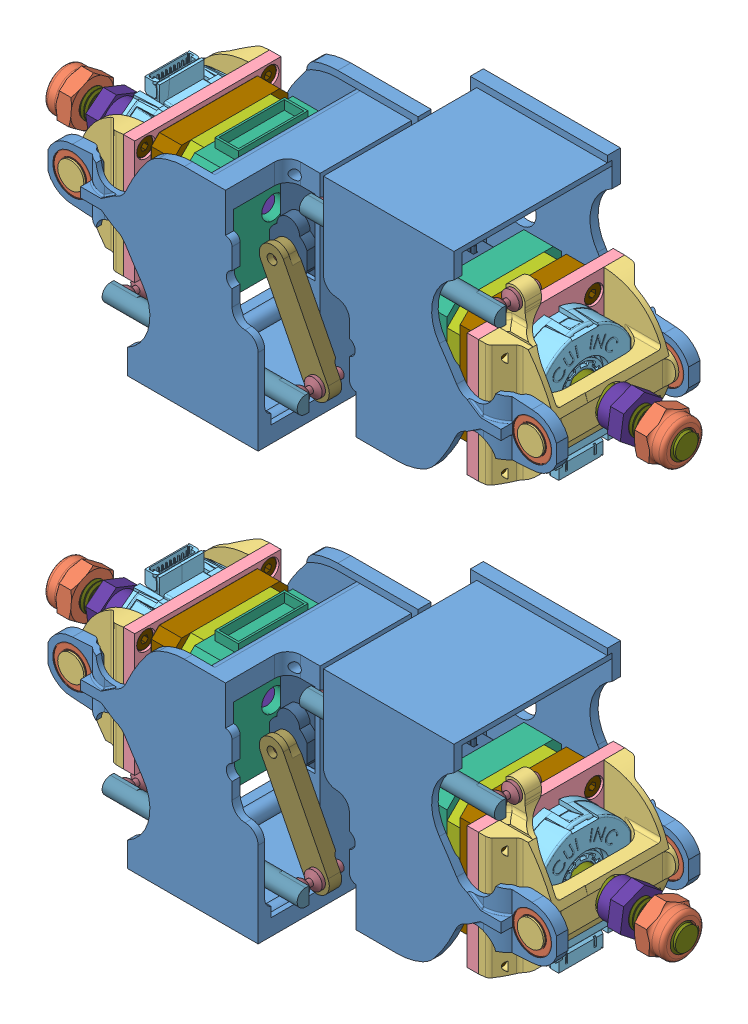
SolidWorks assembly Chassis assembly, configuration Default. Lengths in mm.
Overall size (191.69 235 56).
145 component instances, 22 part files, 13 mates.
Components (placement in the parent):
- Chassis test-1: Chassis test [Default] at (243.7771 53.5419 144.9744) size (100.25 235 0)
- Module Assembly-1: Module Assembly [Default] at (19.8721 170.9374 177.4744) x (0 1 0) z (-1 0 0) size (68.25 51.28 97.81)
  - Housing-1: Housing [Default] at origin size (64.25 48.5 67.91)
  - Bearing 12x8-1: Bearing 12x8 [Default] at (0 -18.25 0.75) x (-0.914388 0 0.40484) z (-0.40484 0 -0.914388) size (12 3.5 12)
  - Spindle-1: Spindle [Default] at (0 2 0.75) size (49.04 45 20.5)
  - Spindle base-1: Spindle base [Default] at (0 2 -15.25) x (-1 0 0) z (0 -1 0) size (37.62 3.5 44.8)
  - Encoder-1: Encoder [Défaut] at (0 2 -12.48) x (0 1 0) z (0 0 1) size (28.68 37.25 10.4)
  - Wheel-1: Wheel [Default] at (0 2 -8.55) x (0.929787 0.368098 0) z (0.368098 -0.929787 0) size (81.5 31 81.5) (hidden)
  - Stepper Nema14-1: Stepper Nema14 [Predeterminado] at (4.764 -15.5 -30.1157) x (-1 0 0) z (0 1 0) size (37.8 40 35)
    - nema14_base-1: nema14_base [Predeterminado] at (-12.736 -8.6343 35) size (37.8 9 35)
    - nema14_centro-1: nema14_centro [Predeterminado] at (-12.736 0.3657 35) size (35 4 35)
    - nema14_eje-1: nema14_eje [Predeterminado] at (4.764 -6.6343 17.5) x (0 1 0) z (-0.939004 0 0.343907) size (38 5 5)
    - nema14_techo-1: nema14_techo [Predeterminado] at (-12.736 4.3657 35) size (35 9 35)
  - Servo motor-1: Servo motor [Default] at (-25.7048 26.288 -66.0832) x (0 0 1) z (1 0 0) size (11.5 29.2 32.5) (flexible)
    - TowerPro-SG90-Body-1: TowerPro-SG90-Body [Default] at (13.6721 7.288 30.7048) size (11.5 26 32.5)
    - ServoFinalGear-1: ServoFinalGear [Default] at (13.6721 33.288 25.7048) x (0.607544 0 -0.794286) z (0.794286 0 0.607544) size (4.64 3.2 4.64)
  - Control arm-1: Control arm [Default] at (0 -7.5 -52.4111) x (0.891007 0 0.45399) z (0.45399 0 -0.891007) size (37.9 4.5 7.8)
  - Ball joint assy-1: Ball joint assy [Default] at (-26.7302 -5 -12.8697) x (-0.874356 0 0.485286) z (0.485286 0 0.874356) size (15.43 16.21 22.24) (flexible)
    - Ball-1: Ball [Default] at origin size (5.5 15.11 5.5)
    - Joint-1: Joint [Default] at (-3.8823 13.66 -6.9948) x (0.874356 0 -0.485286) z (0 -1 0) size (5.1 22.6 5.1)
  - Ball joint assy-2: Ball joint assy [Default] at (-26.7302 -5 -66.0308) x (-0.846813 0 0.531891) z (0.531891 0 0.846813) size (16.34 16.21 21.85) (flexible)
    - Ball-1: Ball [Default] at origin size (5.5 15.11 5.5)
    - Joint-1: Joint [Default] at (4.2551 13.66 6.7745) x (-0.846813 0 0.531891) z (0 -1 0) size (5.1 22.6 5.1)
  - Steering rod-1: Steering rod [Default] at (-26.7302 -18.66 -18.4608) x (-0.014502 0.999895 0) z (-0.999895 -0.014502 0) size (3 28.27 3)
  - Wheel adapter-1: Wheel adapter [Default] at (0 2 -13.8175) x (0.291296 -0.956633 0) z (-0.956633 -0.291296 0) size (8.34 40 8.37)
  - Wheel spacer-1: Wheel spacer [Default] at (0 2 12.25) x (0.368098 -0.929787 0) z (0.929787 0.368098 0) size (13.86 8 12)
  - M3x5 din 7984-1: M3x5 din 7984 [Default] at (15.31 20.9 -16.25) x (0.933505 0.358563 0) z (0 0 -1) size (5.5 5.5 7)
  - Housing lid-1: Housing lid [Default] at (0 4 0) x (-1 0 0) z (0 0 1) size (68.25 9.28 69.91)
  - Bearing 12x8-3: Bearing 12x8 [Default] at (0 22.25 0.75) x (-0.914388 0 0.40484) z (0.40484 0 0.914388) size (12 3.5 12)
  - M8 nut-1: M8 nut [Default] at (0 2 16.6825) x (-0.817347 -0.576146 0) z (0 0 1) size (13 16.06 8.5)
  - M3x5 din 7984-2: M3x5 din 7984 [Default] at (15.31 -16.9 -16.25) x (-0.933505 0.358563 0) z (0 0 -1) size (5.5 5.5 7)
  - M3x5 din 7984-3: M3x5 din 7984 [Default] at (-15.31 20.9 -16.25) x (0.933505 -0.358563 0) z (0 0 -1) size (5.5 5.5 7)
  - M3x5 din 7984-4: M3x5 din 7984 [Default] at (-15.31 -16.9 -16.25) x (-0.933505 -0.358563 0) z (0 0 -1) size (5.5 5.5 7)
  - M3x5 din 7984-5: M3x5 din 7984 [Default] at (-13 15 -17.75) x (0.999849 0.017374 0) z (0 0 1) size (5.5 5.5 7)
  - M3x5 din 7984-6: M3x5 din 7984 [Default] at (-13 -11 -17.75) x (-0.999849 0.017374 0) z (0 0 1) size (5.5 5.5 7)
  - M3x5 din 7984-7: M3x5 din 7984 [Default] at (13 15 -17.75) x (0.999849 -0.017374 0) z (0 0 1) size (5.5 5.5 7)
  - M3x5 din 7984-8: M3x5 din 7984 [Default] at (13 -11 -17.75) x (-0.999849 -0.017374 0) z (0 0 1) size (5.5 5.5 7)
- Module Assembly-2: Module Assembly [Default] at (19.8721 40.1874 177.4744) x (0 1 0) z (-1 0 0) size (68.25 51.28 97.81)
  - Housing-1: Housing [Default] at origin size (64.25 48.5 67.91)
  - Bearing 12x8-1: Bearing 12x8 [Default] at (0 -18.25 0.75) x (-0.914388 0 0.40484) z (-0.40484 0 -0.914388) size (12 3.5 12)
  - Spindle-1: Spindle [Default] at (0 2 0.75) size (49.04 45 20.5)
  - Spindle base-1: Spindle base [Default] at (0 2 -15.25) x (-1 0 0) z (0 -1 0) size (37.62 3.5 44.8)
  - Encoder-1: Encoder [Défaut] at (0 2 -12.48) x (0 1 0) z (0 0 1) size (28.68 37.25 10.4)
  - Wheel-1: Wheel [Default] at (0 2 -8.55) x (0.929787 0.368098 0) z (0.368098 -0.929787 0) size (81.5 31 81.5) (hidden)
  - Stepper Nema14-1: Stepper Nema14 [Predeterminado] at (4.764 -15.5 -30.1157) x (-1 0 0) z (0 1 0) size (37.8 40 35)
    - nema14_base-1: nema14_base [Predeterminado] at (-12.736 -8.6343 35) size (37.8 9 35)
    - nema14_centro-1: nema14_centro [Predeterminado] at (-12.736 0.3657 35) size (35 4 35)
    - nema14_eje-1: nema14_eje [Predeterminado] at (4.764 -6.6343 17.5) x (0 1 0) z (-0.939004 0 0.343907) size (38 5 5)
    - nema14_techo-1: nema14_techo [Predeterminado] at (-12.736 4.3657 35) size (35 9 35)
  - Servo motor-1: Servo motor [Default] at (-25.7048 26.288 -66.0832) x (0 0 1) z (1 0 0) size (11.5 29.2 32.5) (flexible)
    - TowerPro-SG90-Body-1: TowerPro-SG90-Body [Default] at (13.6721 7.288 30.7048) size (11.5 26 32.5)
    - ServoFinalGear-1: ServoFinalGear [Default] at (13.6721 33.288 25.7048) x (0.607544 0 -0.794286) z (0.794286 0 0.607544) size (4.64 3.2 4.64)
  - Control arm-1: Control arm [Default] at (0 -7.5 -52.4111) x (0.891007 0 0.45399) z (0.45399 0 -0.891007) size (37.9 4.5 7.8)
  - Ball joint assy-1: Ball joint assy [Default] at (-26.7302 -5 -12.8697) x (-0.874356 0 0.485286) z (0.485286 0 0.874356) size (15.43 16.21 22.24) (flexible)
    - Ball-1: Ball [Default] at origin size (5.5 15.11 5.5)
    - Joint-1: Joint [Default] at (-3.8823 13.66 -6.9948) x (0.874356 0 -0.485286) z (0 -1 0) size (5.1 22.6 5.1)
  - Ball joint assy-2: Ball joint assy [Default] at (-26.7302 -5 -66.0308) x (-0.846813 0 0.531891) z (0.531891 0 0.846813) size (16.34 16.21 21.85) (flexible)
    - Ball-1: Ball [Default] at origin size (5.5 15.11 5.5)
    - Joint-1: Joint [Default] at (4.2551 13.66 6.7745) x (-0.846813 0 0.531891) z (0 -1 0) size (5.1 22.6 5.1)
  - Steering rod-1: Steering rod [Default] at (-26.7302 -18.66 -18.4608) x (-0.014502 0.999895 0) z (-0.999895 -0.014502 0) size (3 28.27 3)
  - Wheel adapter-1: Wheel adapter [Default] at (0 2 -13.8175) x (0.291296 -0.956633 0) z (-0.956633 -0.291296 0) size (8.34 40 8.37)
  - Wheel spacer-1: Wheel spacer [Default] at (0 2 12.25) x (0.368098 -0.929787 0) z (0.929787 0.368098 0) size (13.86 8 12)
  - M3x5 din 7984-1: M3x5 din 7984 [Default] at (15.31 20.9 -16.25) x (0.933505 0.358563 0) z (0 0 -1) size (5.5 5.5 7)
  - Housing lid-1: Housing lid [Default] at (0 4 0) x (-1 0 0) z (0 0 1) size (68.25 9.28 69.91)
  - Bearing 12x8-3: Bearing 12x8 [Default] at (0 22.25 0.75) x (-0.914388 0 0.40484) z (0.40484 0 0.914388) size (12 3.5 12)
  - M8 nut-1: M8 nut [Default] at (0 2 16.6825) x (-0.817347 -0.576146 0) z (0 0 1) size (13 16.06 8.5)
  - M3x5 din 7984-2: M3x5 din 7984 [Default] at (15.31 -16.9 -16.25) x (-0.933505 0.358563 0) z (0 0 -1) size (5.5 5.5 7)
  - M3x5 din 7984-3: M3x5 din 7984 [Default] at (-15.31 20.9 -16.25) x (0.933505 -0.358563 0) z (0 0 -1) size (5.5 5.5 7)
  - M3x5 din 7984-4: M3x5 din 7984 [Default] at (-15.31 -16.9 -16.25) x (-0.933505 -0.358563 0) z (0 0 -1) size (5.5 5.5 7)
  - M3x5 din 7984-5: M3x5 din 7984 [Default] at (-13 15 -17.75) x (0.999849 0.017374 0) z (0 0 1) size (5.5 5.5 7)
  - M3x5 din 7984-6: M3x5 din 7984 [Default] at (-13 -11 -17.75) x (-0.999849 0.017374 0) z (0 0 1) size (5.5 5.5 7)
  - M3x5 din 7984-7: M3x5 din 7984 [Default] at (13 15 -17.75) x (0.999849 -0.017374 0) z (0 0 1) size (5.5 5.5 7)
  - M3x5 din 7984-8: M3x5 din 7984 [Default] at (13 -11 -17.75) x (-0.999849 -0.017374 0) z (0 0 1) size (5.5 5.5 7)
- Module Assembly-3: Module Assembly [Default] at (159.1944 170.9374 177.4744) x (0 -1 0) z (1 0 0) size (68.25 51.28 97.81)
  - Housing-1: Housing [Default] at origin size (64.25 48.5 67.91)
  - Bearing 12x8-1: Bearing 12x8 [Default] at (0 -18.25 0.75) x (-0.914388 0 0.40484) z (-0.40484 0 -0.914388) size (12 3.5 12)
  - Spindle-1: Spindle [Default] at (0 2 0.75) size (49.04 45 20.5)
  - Spindle base-1: Spindle base [Default] at (0 2 -15.25) x (-1 0 0) z (0 -1 0) size (37.62 3.5 44.8)
  - Encoder-1: Encoder [Défaut] at (0 2 -12.48) x (0 1 0) z (0 0 1) size (28.68 37.25 10.4)
  - Wheel-1: Wheel [Default] at (0 2 -8.55) x (0.929787 0.368098 0) z (0.368098 -0.929787 0) size (81.5 31 81.5) (hidden)
  - Stepper Nema14-1: Stepper Nema14 [Predeterminado] at (4.764 -15.5 -30.1157) x (-1 0 0) z (0 1 0) size (37.8 40 35)
    - nema14_base-1: nema14_base [Predeterminado] at (-12.736 -8.6343 35) size (37.8 9 35)
    - nema14_centro-1: nema14_centro [Predeterminado] at (-12.736 0.3657 35) size (35 4 35)
    - nema14_eje-1: nema14_eje [Predeterminado] at (4.764 -6.6343 17.5) x (0 1 0) z (-0.939004 0 0.343907) size (38 5 5)
    - nema14_techo-1: nema14_techo [Predeterminado] at (-12.736 4.3657 35) size (35 9 35)
  - Servo motor-1: Servo motor [Default] at (-25.7048 26.288 -66.0832) x (0 0 1) z (1 0 0) size (11.5 29.2 32.5) (flexible)
    - TowerPro-SG90-Body-1: TowerPro-SG90-Body [Default] at (13.6721 7.288 30.7048) size (11.5 26 32.5)
    - ServoFinalGear-1: ServoFinalGear [Default] at (13.6721 33.288 25.7048) x (0.607544 0 -0.794286) z (0.794286 0 0.607544) size (4.64 3.2 4.64)
  - Control arm-1: Control arm [Default] at (0 -7.5 -52.4111) x (0.891007 0 0.45399) z (0.45399 0 -0.891007) size (37.9 4.5 7.8)
  - Ball joint assy-1: Ball joint assy [Default] at (-26.7302 -5 -12.8697) x (-0.874356 0 0.485286) z (0.485286 0 0.874356) size (15.43 16.21 22.24) (flexible)
    - Ball-1: Ball [Default] at origin size (5.5 15.11 5.5)
    - Joint-1: Joint [Default] at (-3.8823 13.66 -6.9948) x (0.874356 0 -0.485286) z (0 -1 0) size (5.1 22.6 5.1)
  - Ball joint assy-2: Ball joint assy [Default] at (-26.7302 -5 -66.0308) x (-0.846813 0 0.531891) z (0.531891 0 0.846813) size (16.34 16.21 21.85) (flexible)
    - Ball-1: Ball [Default] at origin size (5.5 15.11 5.5)
    - Joint-1: Joint [Default] at (4.2551 13.66 6.7745) x (-0.846813 0 0.531891) z (0 -1 0) size (5.1 22.6 5.1)
  - Steering rod-1: Steering rod [Default] at (-26.7302 -18.66 -18.4608) x (-0.014502 0.999895 0) z (-0.999895 -0.014502 0) size (3 28.27 3)
  - Wheel adapter-1: Wheel adapter [Default] at (0 2 -13.8175) x (0.291296 -0.956633 0) z (-0.956633 -0.291296 0) size (8.34 40 8.37)
  - Wheel spacer-1: Wheel spacer [Default] at (0 2 12.25) x (0.368098 -0.929787 0) z (0.929787 0.368098 0) size (13.86 8 12)
  - M3x5 din 7984-1: M3x5 din 7984 [Default] at (15.31 20.9 -16.25) x (0.933505 0.358563 0) z (0 0 -1) size (5.5 5.5 7)
  - Housing lid-1: Housing lid [Default] at (0 4 0) x (-1 0 0) z (0 0 1) size (68.25 9.28 69.91)
  - Bearing 12x8-3: Bearing 12x8 [Default] at (0 22.25 0.75) x (-0.914388 0 0.40484) z (0.40484 0 0.914388) size (12 3.5 12)
  - M8 nut-1: M8 nut [Default] at (0 2 16.6825) x (-0.817347 -0.576146 0) z (0 0 1) size (13 16.06 8.5)
  - M3x5 din 7984-2: M3x5 din 7984 [Default] at (15.31 -16.9 -16.25) x (-0.933505 0.358563 0) z (0 0 -1) size (5.5 5.5 7)
  - M3x5 din 7984-3: M3x5 din 7984 [Default] at (-15.31 20.9 -16.25) x (0.933505 -0.358563 0) z (0 0 -1) size (5.5 5.5 7)
  - M3x5 din 7984-4: M3x5 din 7984 [Default] at (-15.31 -16.9 -16.25) x (-0.933505 -0.358563 0) z (0 0 -1) size (5.5 5.5 7)
  - M3x5 din 7984-5: M3x5 din 7984 [Default] at (-13 15 -17.75) x (0.999849 0.017374 0) z (0 0 1) size (5.5 5.5 7)
  - M3x5 din 7984-6: M3x5 din 7984 [Default] at (-13 -11 -17.75) x (-0.999849 0.017374 0) z (0 0 1) size (5.5 5.5 7)
  - M3x5 din 7984-7: M3x5 din 7984 [Default] at (13 15 -17.75) x (0.999849 -0.017374 0) z (0 0 1) size (5.5 5.5 7)
  - M3x5 din 7984-8: M3x5 din 7984 [Default] at (13 -11 -17.75) x (-0.999849 -0.017374 0) z (0 0 1) size (5.5 5.5 7)
- Module Assembly-4: Module Assembly [Default] at (159.1944 40.1874 177.4744) x (0 -1 0) z (1 0 0) size (68.25 51.28 97.81)
  - Housing-1: Housing [Default] at origin size (64.25 48.5 67.91)
  - Bearing 12x8-1: Bearing 12x8 [Default] at (0 -18.25 0.75) x (-0.914388 0 0.40484) z (-0.40484 0 -0.914388) size (12 3.5 12)
  - Spindle-1: Spindle [Default] at (0 2 0.75) size (49.04 45 20.5)
  - Spindle base-1: Spindle base [Default] at (0 2 -15.25) x (-1 0 0) z (0 -1 0) size (37.62 3.5 44.8)
  - Encoder-1: Encoder [Défaut] at (0 2 -12.48) x (0 1 0) z (0 0 1) size (28.68 37.25 10.4)
  - Wheel-1: Wheel [Default] at (0 2 -8.55) x (0.929787 0.368098 0) z (0.368098 -0.929787 0) size (81.5 31 81.5) (hidden)
  - Stepper Nema14-1: Stepper Nema14 [Predeterminado] at (4.764 -15.5 -30.1157) x (-1 0 0) z (0 1 0) size (37.8 40 35)
    - nema14_base-1: nema14_base [Predeterminado] at (-12.736 -8.6343 35) size (37.8 9 35)
    - nema14_centro-1: nema14_centro [Predeterminado] at (-12.736 0.3657 35) size (35 4 35)
    - nema14_eje-1: nema14_eje [Predeterminado] at (4.764 -6.6343 17.5) x (0 1 0) z (-0.939004 0 0.343907) size (38 5 5)
    - nema14_techo-1: nema14_techo [Predeterminado] at (-12.736 4.3657 35) size (35 9 35)
  - Servo motor-1: Servo motor [Default] at (-25.7048 26.288 -66.0832) x (0 0 1) z (1 0 0) size (11.5 29.2 32.5) (flexible)
    - TowerPro-SG90-Body-1: TowerPro-SG90-Body [Default] at (13.6721 7.288 30.7048) size (11.5 26 32.5)
    - ServoFinalGear-1: ServoFinalGear [Default] at (13.6721 33.288 25.7048) x (0.607544 0 -0.794286) z (0.794286 0 0.607544) size (4.64 3.2 4.64)
  - Control arm-1: Control arm [Default] at (0 -7.5 -52.4111) x (0.891007 0 0.45399) z (0.45399 0 -0.891007) size (37.9 4.5 7.8)
  - Ball joint assy-1: Ball joint assy [Default] at (-26.7302 -5 -12.8697) x (-0.874356 0 0.485286) z (0.485286 0 0.874356) size (15.43 16.21 22.24) (flexible)
    - Ball-1: Ball [Default] at origin size (5.5 15.11 5.5)
    - Joint-1: Joint [Default] at (-3.8823 13.66 -6.9948) x (0.874356 0 -0.485286) z (0 -1 0) size (5.1 22.6 5.1)
  - Ball joint assy-2: Ball joint assy [Default] at (-26.7302 -5 -66.0308) x (-0.846813 0 0.531891) z (0.531891 0 0.846813) size (16.34 16.21 21.85) (flexible)
    - Ball-1: Ball [Default] at origin size (5.5 15.11 5.5)
    - Joint-1: Joint [Default] at (4.2551 13.66 6.7745) x (-0.846813 0 0.531891) z (0 -1 0) size (5.1 22.6 5.1)
  - Steering rod-1: Steering rod [Default] at (-26.7302 -18.66 -18.4608) x (-0.014502 0.999895 0) z (-0.999895 -0.014502 0) size (3 28.27 3)
  - Wheel adapter-1: Wheel adapter [Default] at (0 2 -13.8175) x (0.291296 -0.956633 0) z (-0.956633 -0.291296 0) size (8.34 40 8.37)
  - Wheel spacer-1: Wheel spacer [Default] at (0 2 12.25) x (0.368098 -0.929787 0) z (0.929787 0.368098 0) size (13.86 8 12)
  - M3x5 din 7984-1: M3x5 din 7984 [Default] at (15.31 20.9 -16.25) x (0.933505 0.358563 0) z (0 0 -1) size (5.5 5.5 7)
  - Housing lid-1: Housing lid [Default] at (0 4 0) x (-1 0 0) z (0 0 1) size (68.25 9.28 69.91)
  - Bearing 12x8-3: Bearing 12x8 [Default] at (0 22.25 0.75) x (-0.914388 0 0.40484) z (0.40484 0 0.914388) size (12 3.5 12)
  - M8 nut-1: M8 nut [Default] at (0 2 16.6825) x (-0.817347 -0.576146 0) z (0 0 1) size (13 16.06 8.5)
  - M3x5 din 7984-2: M3x5 din 7984 [Default] at (15.31 -16.9 -16.25) x (-0.933505 0.358563 0) z (0 0 -1) size (5.5 5.5 7)
  - M3x5 din 7984-3: M3x5 din 7984 [Default] at (-15.31 20.9 -16.25) x (0.933505 -0.358563 0) z (0 0 -1) size (5.5 5.5 7)
  - M3x5 din 7984-4: M3x5 din 7984 [Default] at (-15.31 -16.9 -16.25) x (-0.933505 -0.358563 0) z (0 0 -1) size (5.5 5.5 7)
  - M3x5 din 7984-5: M3x5 din 7984 [Default] at (-13 15 -17.75) x (0.999849 0.017374 0) z (0 0 1) size (5.5 5.5 7)
  - M3x5 din 7984-6: M3x5 din 7984 [Default] at (-13 -11 -17.75) x (-0.999849 0.017374 0) z (0 0 1) size (5.5 5.5 7)
  - M3x5 din 7984-7: M3x5 din 7984 [Default] at (13 15 -17.75) x (0.999849 -0.017374 0) z (0 0 1) size (5.5 5.5 7)
  - M3x5 din 7984-8: M3x5 din 7984 [Default] at (13 -11 -17.75) x (-0.999849 -0.017374 0) z (0 0 1) size (5.5 5.5 7)
Mates (geometry in assembly coordinates):
- Coincident1: coincident: plane of Chassis test-1 through (243.7771 53.5419 149.9744) normal (0 0 1); plane of Module Assembly-1/Housing lid-1 through (19.8721 170.9374 149.9744) normal (0 0 -1)
- Parallel2: parallel: line of Chassis test-1 through (139.5332 221.6874 149.9744) axis (-1 0 0); line of Module Assembly-1/Housing lid-1 through (81.5332 195.6874 149.9744) axis (-1 0 0)
- Coincident4: coincident: plane of Chassis test-1 through (39.5332 221.6874 149.9744) normal (-1 0 0); plane of Module Assembly-1/Housing lid-1 through (39.5332 170.9374 152.4744) normal (-1 0 0)
- Coincident6: coincident: plane of Chassis test-1 through (243.7771 53.5419 149.9744) normal (0 0 1); plane of Module Assembly-2/Housing lid-1 through (19.8721 40.1874 149.9744) normal (0 0 -1)
- Coincident7: coincident: plane of Chassis test-1 through (39.5332 221.6874 149.9744) normal (-1 0 0); plane of Module Assembly-2/Housing lid-1 through (39.5332 40.1874 152.4744) normal (-1 0 0)
- Distance2: distance = 10 mm: plane of Module Assembly-2/Housing lid-1 through (19.8721 -3.3126 153.9744) normal (0 -1 0); plane of Chassis test-1 through (39.5332 -13.3126 149.9744) normal (0 -1 0)
- Coincident9: coincident: plane of Chassis test-1 through (243.7771 53.5419 149.9744) normal (0 0 1); plane of Module Assembly-3/Housing lid-1 through (159.1944 170.9374 149.9744) normal (0 0 -1)
- Coincident10: coincident: plane of Chassis test-1 through (139.5332 221.6874 149.9744) normal (1 0 0); plane of Module Assembly-3/Housing lid-1 through (139.5332 170.9374 152.4744) normal (1 0 0)
- Distance3: distance = 26 mm: plane of Module Assembly-1/Housing lid-1 through (19.8721 195.6874 153.9744) normal (0 1 0); plane of Chassis test-1 through (39.5332 221.6874 149.9744) normal (0 1 0)
- Concentric1: concentric: circle of Module Assembly-1/Wheel adapter-1; circle of Module Assembly-3/Wheel adapter-1
- Coincident13: coincident: plane of Chassis test-1 through (243.7771 53.5419 149.9744) normal (0 0 1); plane of Module Assembly-4/Housing lid-1 through (159.1944 40.1874 149.9744) normal (0 0 -1)
- Coincident14: coincident: plane of Chassis test-1 through (139.5332 221.6874 149.9744) normal (1 0 0); plane of Module Assembly-4/Housing lid-1 through (139.5332 40.1874 152.4744) normal (1 0 0)
- Concentric2: concentric: circle of Module Assembly-2/Wheel adapter-1; circle of Module Assembly-4/Wheel adapter-1
